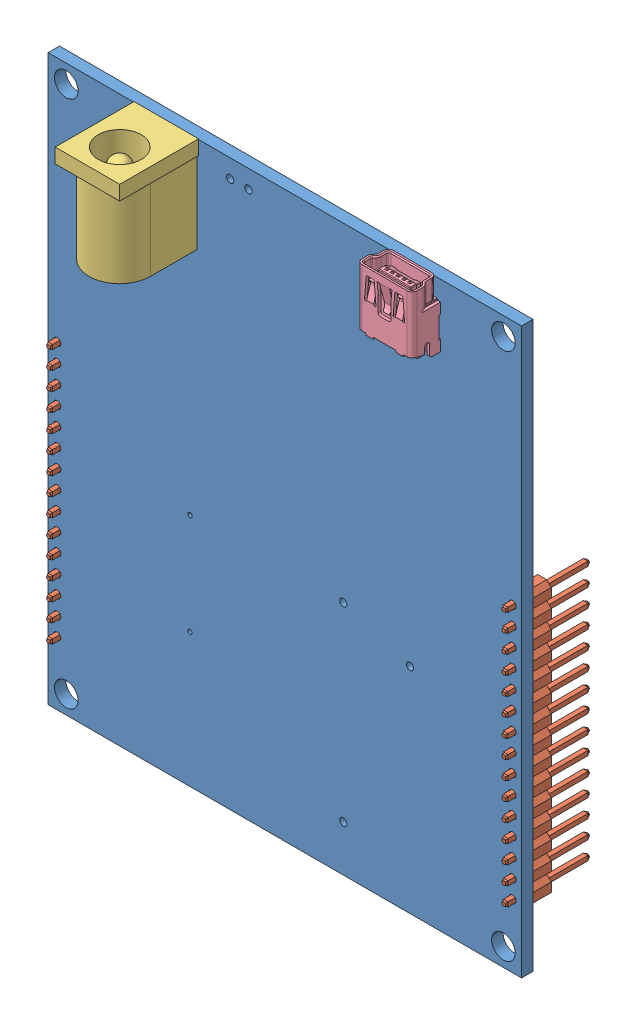
SolidWorks assembly SparkFun ADH8066 Evaluation Board CEL-10741, configuration Default. Lengths in mm.
Overall size (66.04 78.98 21.5).
35 component instances, 4 part files, 12 mates.
Components (placement in the parent):
- adh8066_evalv14-1: adh8066_evalv14 [Default] at origin size (66.04 78.74 1.6)
- Male Header 15 Pin-1: Male Header 15 Pin [Default] at (71.1211 0.2117 -33.682) size (2.54 38.1 11.76)
  - Male Header Pin-1: Male Header Pin [Default] at (-69.8511 8.6783 31.142) size (2.54 2.54 11.76)
  - Male Header Pin-2: Male Header Pin [Default] at (-69.8511 11.2183 31.142) size (2.54 2.54 11.76)
  - Male Header Pin-3: Male Header Pin [Default] at (-69.8511 13.7583 31.142) size (2.54 2.54 11.76)
  - Male Header Pin-4: Male Header Pin [Default] at (-69.8511 16.2983 31.142) size (2.54 2.54 11.76)
  - Male Header Pin-5: Male Header Pin [Default] at (-69.8511 18.8383 31.142) size (2.54 2.54 11.76)
  - Male Header Pin-6: Male Header Pin [Default] at (-69.8511 21.3783 31.142) size (2.54 2.54 11.76)
  - Male Header Pin-7: Male Header Pin [Default] at (-69.8511 23.9183 31.142) size (2.54 2.54 11.76)
  - Male Header Pin-8: Male Header Pin [Default] at (-69.8511 26.4583 31.142) size (2.54 2.54 11.76)
  - Male Header Pin-9: Male Header Pin [Default] at (-69.8511 28.9983 31.142) size (2.54 2.54 11.76)
  - Male Header Pin-10: Male Header Pin [Default] at (-69.8511 31.5383 31.142) size (2.54 2.54 11.76)
  - Male Header Pin-11: Male Header Pin [Default] at (-69.8511 34.0783 31.142) size (2.54 2.54 11.76)
  - Male Header Pin-12: Male Header Pin [Default] at (-69.8511 36.6183 31.142) size (2.54 2.54 11.76)
  - Male Header Pin-13: Male Header Pin [Default] at (-69.8511 39.1583 31.142) size (2.54 2.54 11.76)
  - Male Header Pin-14: Male Header Pin [Default] at (-69.8511 41.6983 31.142) size (2.54 2.54 11.76)
  - Male Header Pin-15: Male Header Pin [Default] at (-69.8511 44.2383 31.142) size (2.54 2.54 11.76)
- Male Header 15 Pin-2: Male Header 15 Pin [Default] at (134.6211 0.2117 -33.682) size (2.54 38.1 11.76)
  - Male Header Pin-1: Male Header Pin [Default] at (-69.8511 8.6783 31.142) size (2.54 2.54 11.76)
  - Male Header Pin-2: Male Header Pin [Default] at (-69.8511 11.2183 31.142) size (2.54 2.54 11.76)
  - Male Header Pin-3: Male Header Pin [Default] at (-69.8511 13.7583 31.142) size (2.54 2.54 11.76)
  - Male Header Pin-4: Male Header Pin [Default] at (-69.8511 16.2983 31.142) size (2.54 2.54 11.76)
  - Male Header Pin-5: Male Header Pin [Default] at (-69.8511 18.8383 31.142) size (2.54 2.54 11.76)
  - Male Header Pin-6: Male Header Pin [Default] at (-69.8511 21.3783 31.142) size (2.54 2.54 11.76)
  - Male Header Pin-7: Male Header Pin [Default] at (-69.8511 23.9183 31.142) size (2.54 2.54 11.76)
  - Male Header Pin-8: Male Header Pin [Default] at (-69.8511 26.4583 31.142) size (2.54 2.54 11.76)
  - Male Header Pin-9: Male Header Pin [Default] at (-69.8511 28.9983 31.142) size (2.54 2.54 11.76)
  - Male Header Pin-10: Male Header Pin [Default] at (-69.8511 31.5383 31.142) size (2.54 2.54 11.76)
  - Male Header Pin-11: Male Header Pin [Default] at (-69.8511 34.0783 31.142) size (2.54 2.54 11.76)
  - Male Header Pin-12: Male Header Pin [Default] at (-69.8511 36.6183 31.142) size (2.54 2.54 11.76)
  - Male Header Pin-13: Male Header Pin [Default] at (-69.8511 39.1583 31.142) size (2.54 2.54 11.76)
  - Male Header Pin-14: Male Header Pin [Default] at (-69.8511 41.6983 31.142) size (2.54 2.54 11.76)
  - Male Header Pin-15: Male Header Pin [Default] at (-69.8511 44.2383 31.142) size (2.54 2.54 11.76)
- DC Barrel Power Jack-1: DC Barrel Power Jack [Default] at (20.9937 65.3291 1.6) x (-1 0 0) z (0 1 0) size (9.51 14.5 13.83)
- USB Mini-B Female-1: USB Mini-B Female [Default] at (50.8771 78.984 3.6) x (-1 0 0) z (0 1 0) size (7.7 5.76 9)
Mates (geometry in assembly coordinates):
- Coincident1: coincident anti-aligned: plane of adh8066_evalv14-1 through (0 0 0) normal (0 0 -1); plane of Male Header 15 Pin-1/Male Header Pin-15 through (2.54 45.72 0) normal (0 0 1)
- Parallel1: parallel aligned: plane of adh8066_evalv14-1 through (0 78.74 1.6) normal (-1 0 0); plane of Male Header 15 Pin-1/Male Header Pin-15 through (0 43.815 0) normal (-1 0 0)
- Concentric1: concentric anti-aligned: cylinder of adh8066_evalv14-1 through (1.27 44.45 1.6) axis (0 0 -1) radius 0.51; circle of Male Header 15 Pin-1/Male Header Pin-15
- Coincident3: coincident anti-aligned: plane of adh8066_evalv14-1 through (0 0 0) normal (0 0 -1); plane of Male Header 15 Pin-2/Male Header Pin-15 through (66.04 45.72 0) normal (0 0 1)
- Parallel2: parallel aligned: plane of adh8066_evalv14-1 through (66.04 0 1.6) normal (1 0 0); plane of Male Header 15 Pin-2/Male Header Pin-15 through (66.04 43.815 0) normal (1 0 0)
- Concentric2: concentric anti-aligned: cylinder of adh8066_evalv14-1 through (64.77 44.45 1.6) axis (0 0 -1) radius 0.51; circle of Male Header 15 Pin-2/Male Header Pin-15
- Coincident5: coincident anti-aligned: plane of adh8066_evalv14-1 through (0 0 1.6) normal (0 0 1); plane of DC Barrel Power Jack-1 through (20.9937 78.8291 1.6) normal (0 0 -1)
- Parallel3: parallel aligned: line of adh8066_evalv14-1 through (66.04 78.74 1.6) axis (-1 0 0); line of DC Barrel Power Jack-1 through (20.9937 78.8291 1.6) axis (-1 0 0)
- Parallel4: parallel aligned: line of adh8066_evalv14-1 through (0 78.74 1.6) axis (0 -1 0); line of DC Barrel Power Jack-1 through (12.2338 76.8012 1.6) axis (0 -1 0)
- Coincident8: coincident anti-aligned: plane of adh8066_evalv14-1 through (0 0 1.6) normal (0 0 1); plane of USB Mini-B Female-1 through (47.0271 76.234 1.6) normal (0 0 -1)
- Parallel5: parallel anti-aligned: line of adh8066_evalv14-1 through (66.04 78.74 1.6) axis (-1 0 0); line of USB Mini-B Female-1 through (48.2421 78.984 1.65) axis (1 0 0)
- Parallel6: parallel aligned: line of adh8066_evalv14-1 through (66.04 0 1.6) axis (0 1 0); line of USB Mini-B Female-1 through (54.7271 71.484 1.8) axis (0 1 0)
